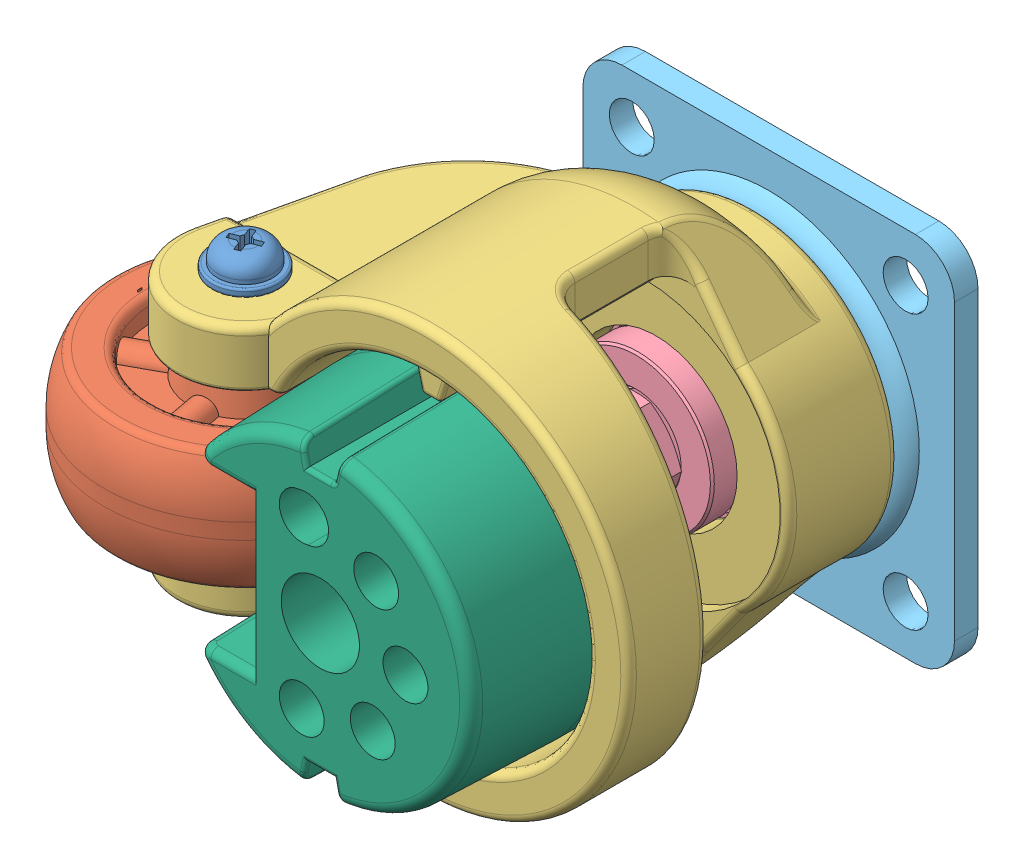
SolidWorks assembly Колесо в сборе, configuration По умолчанию. Lengths in mm.
Overall size (143.32 104 121.11).
6 component instances, 6 part files, 7 mates.
Components (placement in the parent):
- Винт-1: Винт [По умолчанию] at (52.7885 63.2962 -0.8027) size (17.1 79.04 17.1)
- Колесо-1: Колесо [По умолчанию] at (52.7885 63.6942 -0.8027) size (72 34 72)
- Корпус-1: Корпус [По умолчанию] at (52.7885 63.2962 -0.8027) size (124.82 104 92.5)
- Ось-1: Ось [По умолчанию] at (52.7885 63.2962 -0.9143) x (0.996231 0.086745 0) z (0 0 1) size (41 41 95.9)
- Платформа-1: Платформа [По умолчанию] at (52.7885 63.2962 -0.6072) size (95 95 13.8)
- Пятка-1: Пятка [По умолчанию] at (52.7885 63.2962 -0.0085) size (72.11 78.21 50.12)
Mates (geometry in assembly coordinates):
- Совпадение1: coincident anti-aligned: plane of Винт-1 through (-2.2115 95.7962 59.1973) normal (0 -1 0); plane of Корпус-1 through (-1.7756 95.7962 59.7161) normal (0 1 0)
- Концентричный1: concentric anti-aligned: cylinder of Винт-1 through (-2.2115 30.7962 59.1973) axis (0 1 0) radius 6; circle of Корпус-1
- Концентричный2: concentric anti-aligned: cylinder of Винт-1 through (-2.2115 30.7962 59.1973) axis (0 1 0) radius 6; circle of Колесо-1
- Концентричный4: concentric aligned: circle of Корпус-1; circle of Пятка-1
- Концентричный5: concentric aligned: circle of Корпус-1; circle of Платформа-1
- Концентричный6: concentric aligned: circle of Ось-1; circle of Платформа-1
- Параллельность1: parallel aligned: plane of Корпус-1 through (1.1107 93.7962 36.7434) normal (0 1 0); plane of Платформа-1 through (5.2885 110.7962 -25.6072) normal (0 1 0)
